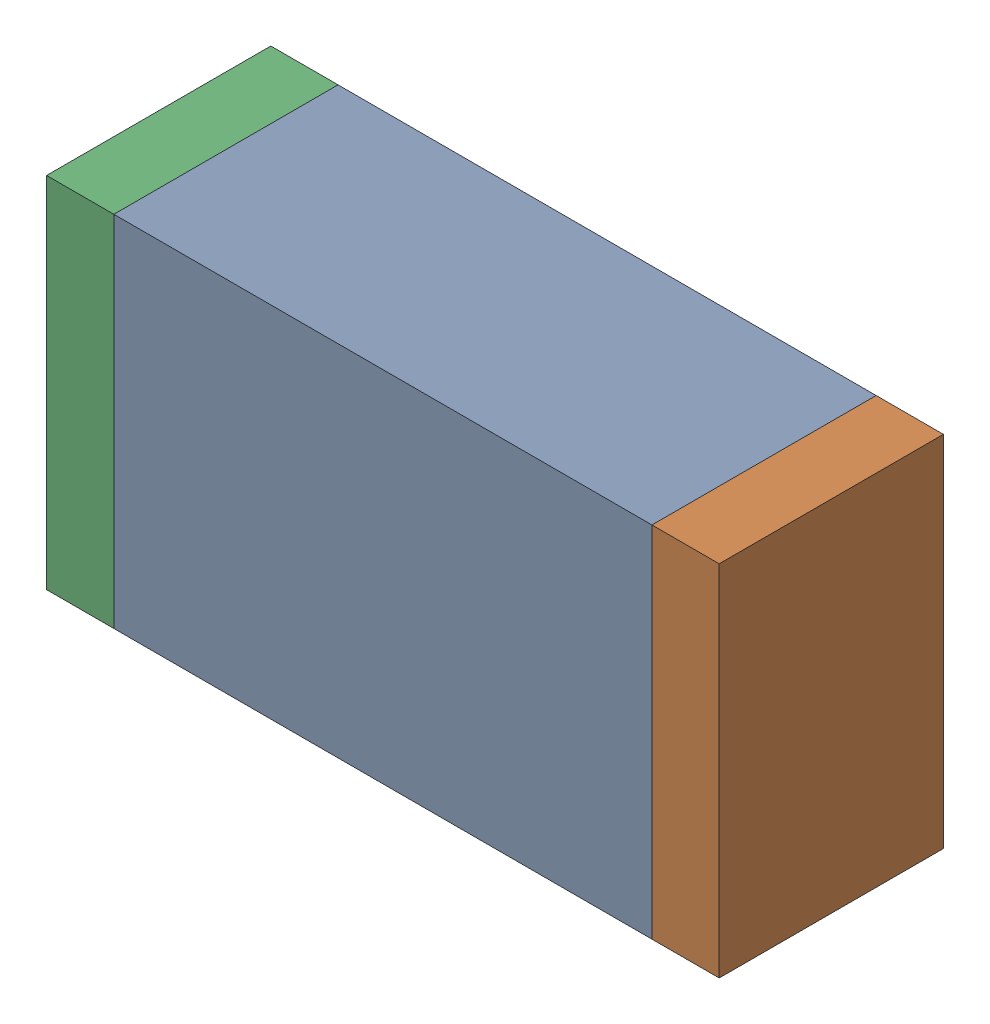
SolidWorks assembly L1, configuration Default. Lengths in mm.
Overall size (1.5 0.8 0.5).
6 component instances, 2 part files, 0 mates.
Components (placement in the parent):
- 836752368-1: 836752368 [Default] at (107.05 7.55 0) size (1.2 0.8 0.5)
  - Extruded-1: Extruded [Default] at origin size (1.2 0.8 0.5)
- 836752496-1: 836752496 [Default] at (107.725 7.55 0) size (0.15 0.8 0.5)
  - Extruded_2-1: Extruded_2 [Default] at origin size (0.15 0.8 0.5)
- 836752496-2: 836752496 [Default] at (106.375 7.55 0) size (0.15 0.8 0.5)
  - Extruded_2-1: Extruded_2 [Default] at origin size (0.15 0.8 0.5)
